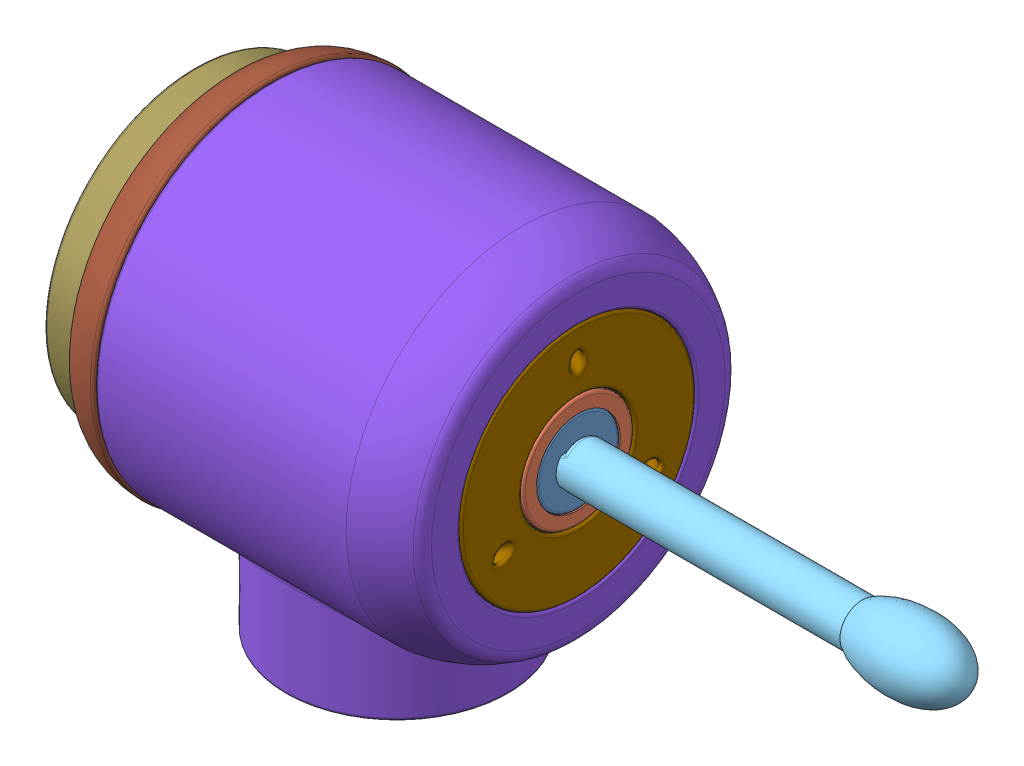
SolidWorks assembly Drill Assembly, configuration Default. Lengths in mm.
Overall size (27.75 14.83 12.65).
16 component instances, 14 part files, 27 mates.
Components (placement in the parent):
- Chuck-2: Chuck [Default] at (-14.7562 4.439 -3.0244) x (1 0 0) z (0 -1 0) size (12 3 3)
- Spindle-1: Spindle [Default] at (-18.2562 4.439 -3.0244) x (1 0 0) z (0 0.494634 0.869101) size (12 4.7 4.61)
- Rotor-1: Rotor [Default] at (-11.7562 4.439 -3.0244) size (4.02 10.24 10.24)
- Chuck slider-1: Chuck slider [Default] at (-14.6486 4.439 -3.0244) x (1 0 0) z (0 -0.313569 -0.949565) size (2 2.2 2.2)
- Burr-2: Burr [Default] at (-10.7562 4.439 -3.0244) size (22.04 2.98 2.98)
- Ball bearings-1: Ball bearings [Default] at (-6.5062 4.439 -3.0244) size (2.5 7 7)
- Ball bearings-2: Ball bearings [Default] at (-13.0062 4.439 -3.0244) x (-1 0 0) z (0 0.924225 0.381849) size (2.5 7 7)
- O-ring-1: O-ring [Default] at (-6.2562 4.439 -3.0244) size (1 9 9)
- O-ring-2: O-ring [Default] at (-13.2562 4.439 -3.0244) x (-1 0 0) z (0 -0.924225 -0.381849) size (1 9 9)
- Head-1: Head [Default] at (-2.7562 4.439 -3.0244) size (11.14 14.83 12.65)
- Water cap-1: Water cap [Default] at (-2.7562 4.439 -3.0244) size (2 10.65 10.65)
- Water lock-1: Water lock [Default] at (-2.7562 4.439 -3.0244) size (3 10.73 10.65)
- Back-cap-1: Back-cap [Default] at (-13.7562 4.439 -3.0244) size (2.98 12.64 12.64)
- Back-cap tab-1: Back-cap tab [Default] at (-16.0062 4.439 -3.0244) x (1 0 0) z (0 0.076281 0.997086) size (3.25 11.57 11.57)
- Sacraficial anode-1: Sacraficial anode [Default] at (-14.7562 4.439 -3.0244) size (0.5 9.77 9.77)
- Back-cap spring-2: Back-cap spring [Default] at (-15.0656 4.4342 -2.9768) size (1.21 11.14 9.66)
Mates (geometry in assembly coordinates):
- Concentric4: concentric: cylinder of Chuck-2 through (-14.7562 4.439 -3.0244) axis (-1 0 0) radius 1.5; cylinder of Spindle-1 through (-1.2562 4.439 -3.0244) axis (-1 0 0) radius 1.5
- Coincident10: coincident: plane of Chuck-2 through (-2.7562 9.439 -3.0244) normal (1 0 0); plane of Spindle-1 through (-2.7562 3.704 -8.3592) normal (1 0 0)
- Concentric5: concentric: cylinder of Spindle-1 through (-18.2562 4.439 -3.0244) axis (-1 0 0) radius 2.5; cylinder of Rotor-1 through (-11.7562 4.439 -3.0244) axis (1 0 0) radius 2.5
- Coincident11: coincident: circle of Spindle-1; plane of Rotor-1 through (-11.7562 4.439 -3.0244) normal (-1 0 0)
- Concentric6: concentric: cylinder of Chuck-2 through (-14.7562 4.439 -3.0244) axis (-1 0 0) radius 1.1; cylinder of Chuck slider-1 through (-12.1486 4.439 -3.0244) axis (-1 0 0) radius 1.1
- Concentric7: concentric: cylinder of Chuck-2 through (-6.7562 4.439 -3.0244) axis (1 0 0) radius 0.8; cylinder of Burr-2 through (-10.7562 4.439 -3.0244) axis (-1 0 0) radius 0.8
- Coincident13: coincident: plane of Chuck-2 through (-8.7562 4.5893 -3.5013) normal (-1 0 0); plane of Burr-2 through (-8.7562 5.239 -3.0244) normal (1 0 0)
- Coincident15: coincident: plane of Rotor-1 through (-7.7562 4.439 -3.0244) normal (1 0 0); plane of Ball bearings-1 through (-7.7562 4.439 -3.0244) normal (-1 0 0)
- Concentric8: concentric: cylinder of Spindle-1 through (-1.2562 4.439 -3.0244) axis (-1 0 0) radius 2; cylinder of Ball bearings-1 through (-5.2562 4.439 -3.0244) axis (-1 0 0) radius 2
- Concentric9: concentric: cylinder of Spindle-1 through (-1.2562 4.439 -3.0244) axis (-1 0 0) radius 2; cylinder of Ball bearings-2 through (-14.2562 4.439 -3.0244) axis (1 0 0) radius 2
- Coincident16: coincident: plane of Rotor-1 through (-11.7562 4.439 -3.0244) normal (-1 0 0); plane of Ball bearings-2 through (-11.7562 4.439 -3.0244) normal (1 0 0)
- Tangent1: tangent: cylinder of Ball bearings-1 through (-5.2562 4.439 -3.0244) axis (-1 0 0) radius 3.5; torus of O-ring-1
- Tangent5: tangent: cylinder of Ball bearings-2 through (-14.2562 4.439 -3.0244) axis (1 0 0) radius 3.5; torus of O-ring-2
- Tangent6: tangent: plane of Ball bearings-2 through (-13.7562 3.1025 0.2104) normal (1 0 0); torus of O-ring-2
- Tangent7: tangent: plane of Ball bearings-1 through (-5.7562 7.939 -3.0244) normal (-1 0 0); torus of O-ring-1
- Coincident17: coincident: plane of Spindle-1 through (-2.7562 3.704 -8.3592) normal (1 0 0); plane of Head-1 through (-2.7562 8.664 -3.0244) normal (1 0 0)
- Concentric10: concentric: cylinder of Spindle-1 through (-1.2562 4.439 -3.0244) axis (-1 0 0) radius 2; cylinder of Head-1 through (-2.7562 4.439 -3.0244) axis (1 0 0) radius 5.325
- Coincident18: coincident: plane of Spindle-1 through (-2.7562 3.704 -8.3592) normal (1 0 0); plane of Water cap-1 through (-2.7562 6.464 -3.0244) normal (1 0 0)
- Concentric11: concentric: cylinder of Head-1 through (-2.7562 4.439 -3.0244) axis (1 0 0) radius 4.225; cylinder of Water cap-1 through (-2.7562 4.439 -3.0244) axis (1 0 0) radius 4.225
- Concentric12: concentric: cylinder of Head-1 through (-2.7562 4.439 -3.0244) axis (1 0 0) radius 5.325; cylinder of Water lock-1 through (-2.7562 4.439 -3.0244) axis (1 0 0) radius 5.325
- Coincident19: coincident: plane of Water cap-1 through (-4.2562 4.439 -3.0244) normal (-1 0 0); plane of Water lock-1 through (-4.2562 6.964 -3.0244) normal (1 0 0)
- Coincident20: coincident: plane of Head-1 through (-13.7562 9.764 -3.0244) normal (-1 0 0); plane of Back-cap-1 through (-13.7562 4.439 -3.0244) normal (1 0 0)
- Concentric14: concentric: cylinder of Back-cap-1 through (-13.7562 4.439 -3.0244) axis (1 0 0) radius 5.325; cylinder of Back-cap tab-1 through (-15.0062 4.439 -3.0244) axis (1 0 0) radius 5.325
- Concentric15: concentric: cylinder of Back-cap tab-1 through (-15.0062 4.439 -3.0244) axis (1 0 0) radius 4.825; cylinder of Sacraficial anode-1 through (-14.2562 4.439 -3.0244) axis (-1 0 0) radius 4.885
- Coincident25: coincident: plane of Back-cap-1 through (-14.2562 4.439 -3.0244) normal (-1 0 0); plane of Sacraficial anode-1 through (-14.2562 4.439 -3.0244) normal (1 0 0)
- Coincident26: coincident: plane of Back-cap-1 through (-13.7562 4.439 -3.0244) normal (1 0 0); plane of Back-cap tab-1 through (-13.7562 10.2124 -2.6586) normal (-1 0 0)
- Concentric16: concentric: cylinder of Head-1 through (-2.7562 4.439 -3.0244) axis (1 0 0) radius 6.325; circle of Back-cap-1
